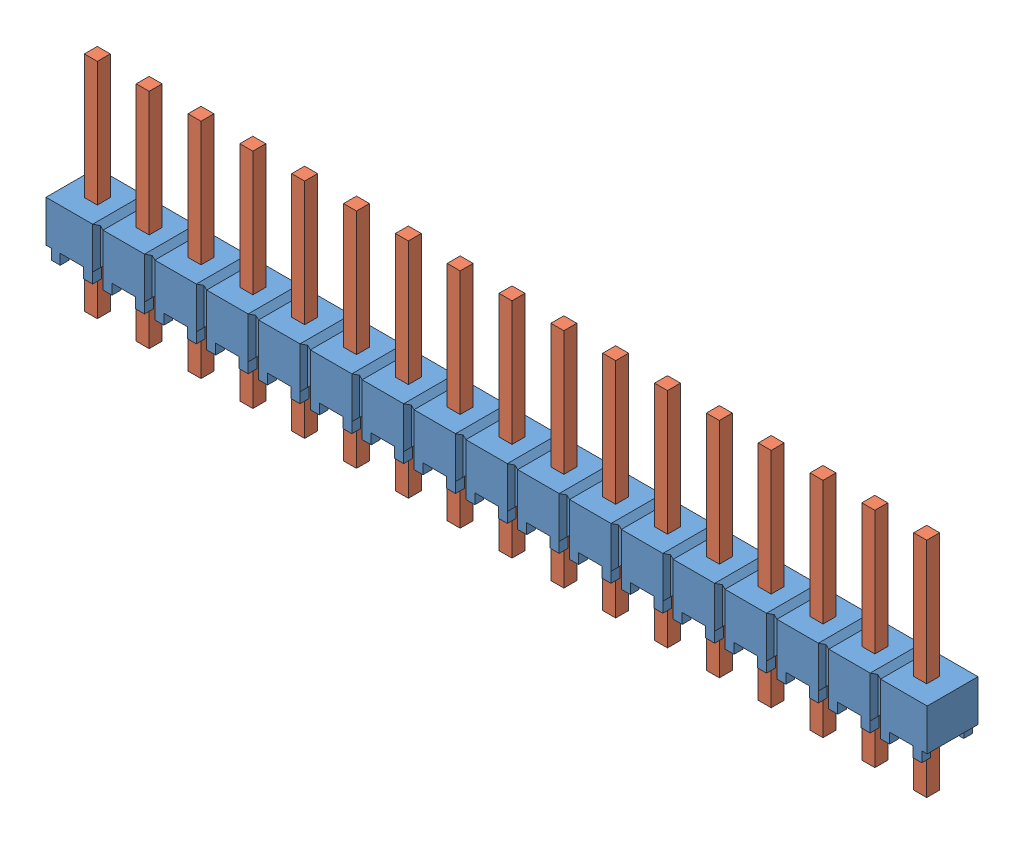
SolidWorks assembly HMTSW_117_07_G_S_240, configuration Default. Lengths in mm.
Overall size (43.18 10.92 2.49).
2 component instances, 2 part files, 0 mates.
Components (placement in the parent):
- _HMTSW_117_07_G_S_240_body_2-1: _HMTSW_117_07_G_S_240_body_2 [Default] at origin size (43.18 2.54 2.49)
- _HMTSW_117_07_S_240_4-1: _HMTSW_117_07_S_240_4 [Default] at (0 -2.286 0) size (41.53 10.92 0.89)
